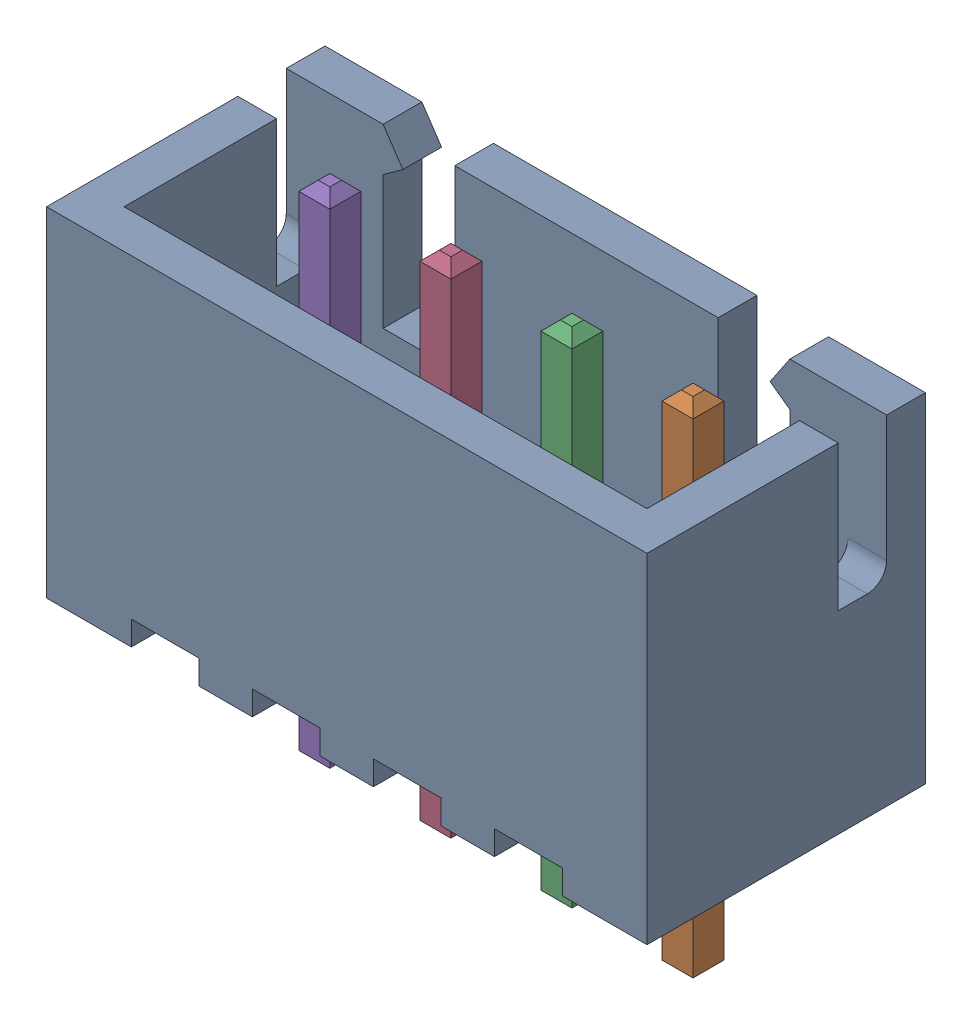
SolidWorks assembly 4 pin Header_2, configuration 4 pin Header_2. Lengths in mm.
Overall size (12.4 10.4 5.75).
5 component instances, 2 part files, 0 mates.
Components (placement in the parent):
- B4B-XH-A (BODY)-1: B4B-XH-A (BODY) [B4B-XH-A (BODY)] at (1.9192 5.3562 13.8157) size (12.4 7 5.75)
- B4B-XH-A (PIN)-1: B4B-XH-A (PIN) [B4B-XH-A (PIN)] at (5.6692 12.3562 13.2907) x (-1 0 0) z (0 0 1) size (0.64 10.4 0.64)
- B4B-XH-A (PIN)-2: B4B-XH-A (PIN) [B4B-XH-A (PIN)] at (3.1692 12.3562 13.2907) x (-1 0 0) z (0 0 1) size (0.64 10.4 0.64)
- B4B-XH-A (PIN)-3: B4B-XH-A (PIN) [B4B-XH-A (PIN)] at (0.6692 12.3562 13.2907) x (-1 0 0) z (0 0 1) size (0.64 10.4 0.64)
- B4B-XH-A (PIN)-4: B4B-XH-A (PIN) [B4B-XH-A (PIN)] at (-1.8308 12.3562 13.2907) x (-1 0 0) z (0 0 1) size (0.64 10.4 0.64)
